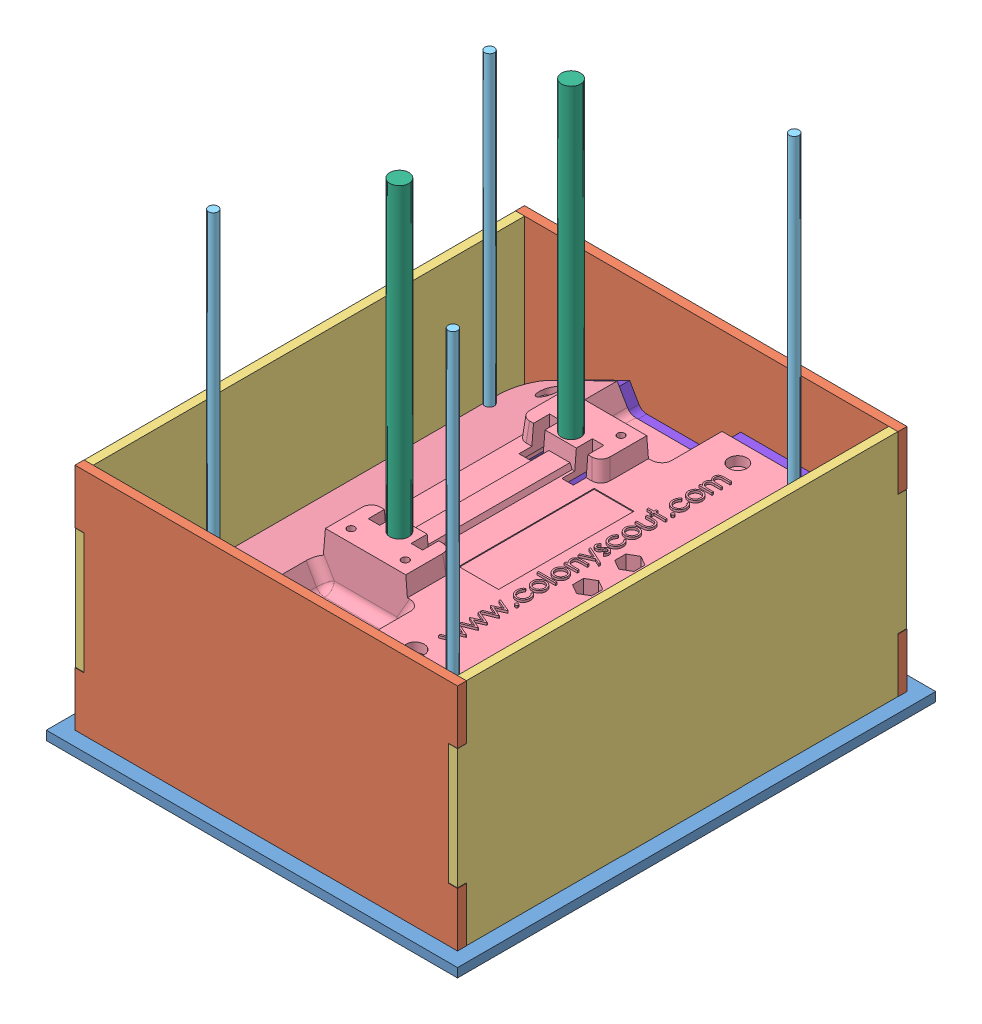
SolidWorks assembly MOLD, CHASSIS, FRONT, configuration Default. Lengths in mm.
Overall size (136.52 169.57 158.75).
15 component instances, 8 part files, 11 mates.
Components (placement in the parent):
- MOLD, Box, FRONT-1: MOLD, Box, FRONT [Default] at (-38.0314 -11.1539 150.9496) x (0 0 1) z (-1 0 0) size (158.75 79.2 136.53)
  - MOLD, Box, Front, Bottom-1: MOLD, Box, Front, Bottom [Default] at (-99.4767 5.4191 48.8108) size (158.75 3 136.53)
  - MOLD, Box, Front, Side1-1: MOLD, Box, Front, Side1 [Default] at (-26.3628 45.0177 48.8108) x (0 0 1) z (-1 0 0) size (127 79.15 3)
  - MOLD, Box, Front, Side1-2: MOLD, Box, Front, Side1 [Default] at (-172.5906 45.0177 48.8108) x (0 0 1) z (-1 0 0) size (127 79.15 3)
  - MOLD, Box, Front, Side2-1: MOLD, Box, Front, Side2 [Default] at (-99.4767 45.0177 110.7614) size (149.12 79.15 3)
  - MOLD, Box, Front, Side2-2: MOLD, Box, Front, Side2 [Default] at (-99.4767 45.0177 -13.1398) size (149.12 79.15 3)
- CHASSIS, UNIBODY, FRONT-1: CHASSIS, UNIBODY, FRONT [Default] at (-38.4706 54.3818 51.4729) x (-1 0 0) z (0 0 1) size (102.23 55.27 121.02)
- MOLD, POURING VENT-1: MOLD, POURING VENT [Default] at (-42.5204 54.3818 -4.8749) size (3.17 101.6 3.17)
- MOLD, POURING SPRUE-1: MOLD, POURING SPRUE [Default] at (-88.6913 60.7318 80.0414) size (6.35 101.6 6.35)
- MOLD, POURING SPRUE-2: MOLD, POURING SPRUE [Default] at (-88.782 60.7318 22.9427) size (6.35 101.6 6.35)
- MOLD, POURING VENT-2: MOLD, POURING VENT [Default] at (-43.0534 54.3818 107.882) size (3.17 101.6 3.17)
- MOLD, POURING VENT-4: MOLD, POURING VENT [Default] at (-132.5157 38.7577 6.2902) size (3.17 101.6 3.17)
- MOLD, POURING VENT-5: MOLD, POURING VENT [Default] at (-132.6086 38.7843 97.9004) size (3.17 101.6 3.17)
- MOLD, box, Front, Mounting Base-1: MOLD, box, Front, Mounting Base [Default] at (-86.8422 2.968 51.4729) size (120.9 3 143.18)
- MOLD, Box, FRONT, Support-1: MOLD, Box, FRONT, Support [Default] at (-38.4706 54.3818 111.5479) size (107.54 56.27 131.55)
Mates (geometry in assembly coordinates):
- Coincident3: coincident anti-aligned: plane of CHASSIS, UNIBODY, FRONT-1 through (-75.1356 60.7318 26.7079) normal (0 1 0); plane of MOLD, POURING SPRUE-1 through (-88.6913 60.7318 80.0414) normal (0 -1 0)
- Coincident4: coincident anti-aligned: plane of CHASSIS, UNIBODY, FRONT-1 through (-38.4706 54.3818 113.0679) normal (0 1 0); plane of MOLD, POURING VENT-1 through (-42.5204 54.3818 -4.8749) normal (0 -1 0)
- Coincident5: coincident aligned: plane of MOLD, POURING SPRUE-1 through (-88.6913 162.3318 80.0414) normal (0 1 0); plane of MOLD, POURING SPRUE-2 through (-88.782 162.3318 22.9427) normal (0 1 0)
- Coincident6: coincident aligned: plane of MOLD, POURING VENT-1 through (-42.5204 155.9818 -4.8749) normal (0 1 0); plane of MOLD, POURING VENT-2 through (-43.0534 155.9818 107.882) normal (0 1 0)
- Coincident10: coincident aligned: plane of CHASSIS, UNIBODY, FRONT-1 through (-38.4706 54.3818 51.4729) normal (0 0 1); plane of MOLD, Box, FRONT-1/MOLD, Box, Front, Bottom-1 through (-86.8422 -5.7348 51.4729) normal (0 0 1)
- Width1: width anti-aligned: plane of MOLD, Box, FRONT-1/MOLD, Box, Front, Side1-2 through (-150.3422 71.9638 -20.1424) normal (0 0 1); plane of MOLD, Box, FRONT-1/MOLD, Box, Front, Side1-1 through (-150.3422 71.9638 123.0882) normal (0 0 -1); plane of MOLD, box, Front, Mounting Base-1 through (-147.2942 4.4666 -20.117) normal (0 0 -1); plane of MOLD, box, Front, Mounting Base-1 through (-147.2942 4.4666 123.0628) normal (0 0 1)
- Coincident12: coincident anti-aligned: plane of MOLD, Box, FRONT-1/MOLD, Box, Front, Side2-1 through (-147.2942 71.9638 123.0882) normal (1 0 0); plane of MOLD, box, Front, Mounting Base-1 through (-147.2942 4.4666 123.0628) normal (-1 0 0)
- Coincident13: coincident anti-aligned: plane of MOLD, box, Front, Mounting Base-1 through (-26.3902 4.4666 -20.117) normal (0 1 0); plane of MOLD, Box, FRONT, Support-1 through (-41.3239 4.4666 -13.6021) normal (0 -1 0)
- Coincident14: coincident anti-aligned: plane of CHASSIS, UNIBODY, FRONT-1 through (-76.2206 41.8718 113.0679) normal (0 -1 0); plane of MOLD, Box, FRONT, Support-1 through (-100.201 41.8718 110.5479) normal (0 1 0)
- Coincident15: coincident anti-aligned: plane of CHASSIS, UNIBODY, FRONT-1 through (-42.776 52.2818 113.0679) normal (-0.99863 -0.052336 0); plane of MOLD, Box, FRONT, Support-1 through (-42.776 52.2818 110.5479) normal (0.99863 0.052336 0)
- Width2: width anti-aligned: plane of MOLD, Box, FRONT, Support-1 through (-100.201 44.8718 116.5479) normal (0 0 1); plane of MOLD, Box, FRONT, Support-1 through (-100.201 44.8718 -13.6021) normal (0 0 -1); plane of MOLD, Box, FRONT-1/MOLD, Box, Front, Side1-2 through (-150.3422 71.9638 -23.1396) normal (0 0 -1); plane of MOLD, Box, FRONT-1/MOLD, Box, Front, Side1-1 through (-150.3422 71.9638 126.0854) normal (0 0 1)
